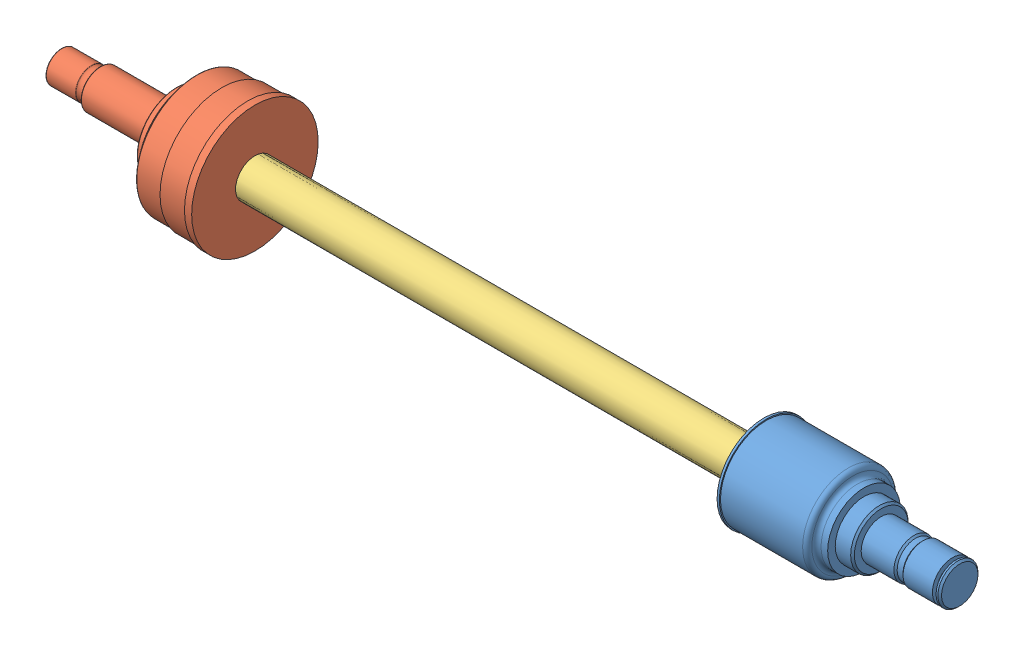
SolidWorks assembly HalfshaftCivicLeft, configuration Default. Lengths in mm.
Overall size (624.85 124.16 124.16).
3 component instances, 3 part files, 2 mates.
Components (placement in the parent):
- CVjointCivicInner-1: CVjointCivicInner [Default] at origin size (136.25 65.07 65.07)
- CVjointCivicOuter-1: CVjointCivicOuter [Default] at (-354 0 0) x (-1 0 0) z (0 -0.656823 -0.754045) size (134.6 88 88)
- AxleLeftRear-1: AxleLeftRear [Default] at (-177 0 0) x (1 0 0) z (0 -0.10869 0.994076) size (354 27 27)
Mates (geometry in assembly coordinates):
- Coincident42685: coincident: point of CVjointCivicInner-1; point of AxleLeftRear-1
- Coincident42684: coincident: point of CVjointCivicOuter-1; point of AxleLeftRear-1
